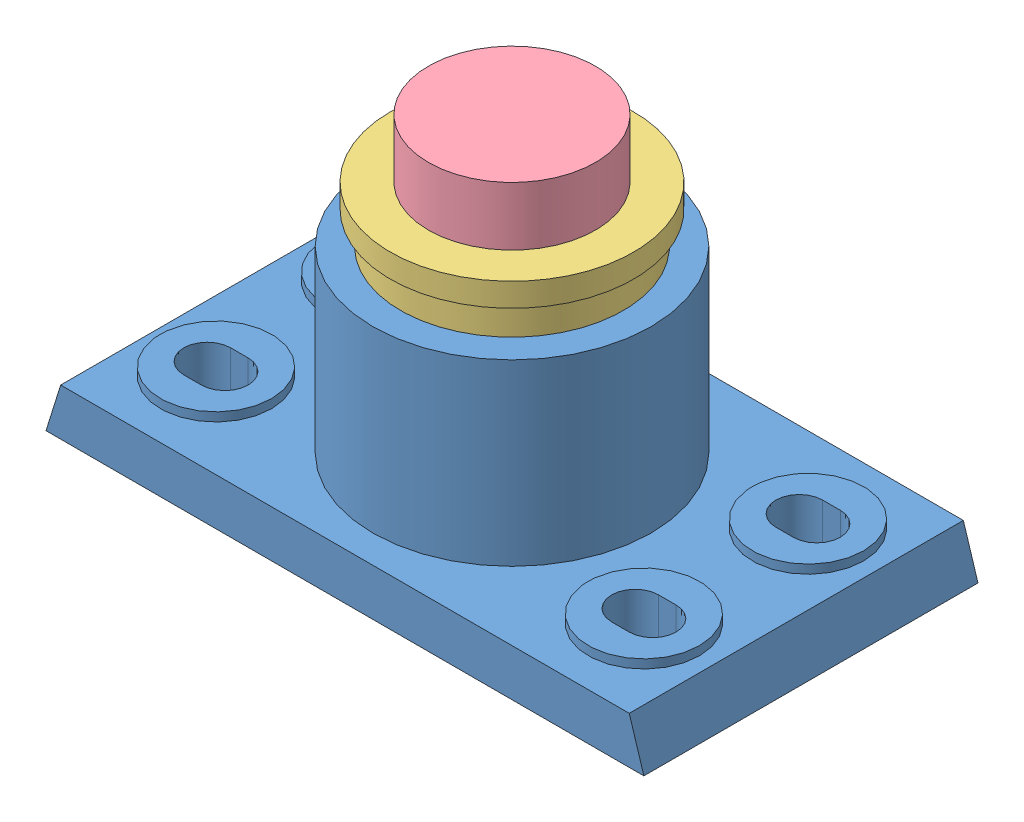
SolidWorks assembly Footstep, configuration Default. Lengths in mm.
Overall size (204 116 114).
4 component instances, 4 part files, 6 mates.
Components (placement in the parent):
- Body-1: Body [Default] at (77.7937 73.0167 209.2824) size (204 77 114)
- Pad-1: Pad [Default] at (55.7937 89.0167 152.2824) size (44 13 44)
- Bush-1: Bush [Default] at (46.7937 92.0167 152.2824) size (83 77 83)
- Shaft-1: Shaft [Default] at (77.7937 189.0167 152.2824) size (57 95 57)
Mates (geometry in assembly coordinates):
- Concentric1: concentric: circle of Body-1; circle of Pad-1
- Lock2: lock: unknown of Body-1; unknown of Pad-1
- Concentric2: concentric anti-aligned: circle of Bush-1; circle of Body-1
- Lock3: lock: unknown of Body-1; unknown of Bush-1
- Coincident4: coincident anti-aligned: plane of Bush-1 through (36.2937 169.0167 152.2824) normal (0 1 0); plane of Shaft-1 through (77.7937 169.0167 152.2824) normal (0 -1 0)
- Lock1: lock: unknown of Bush-1; unknown of Shaft-1
